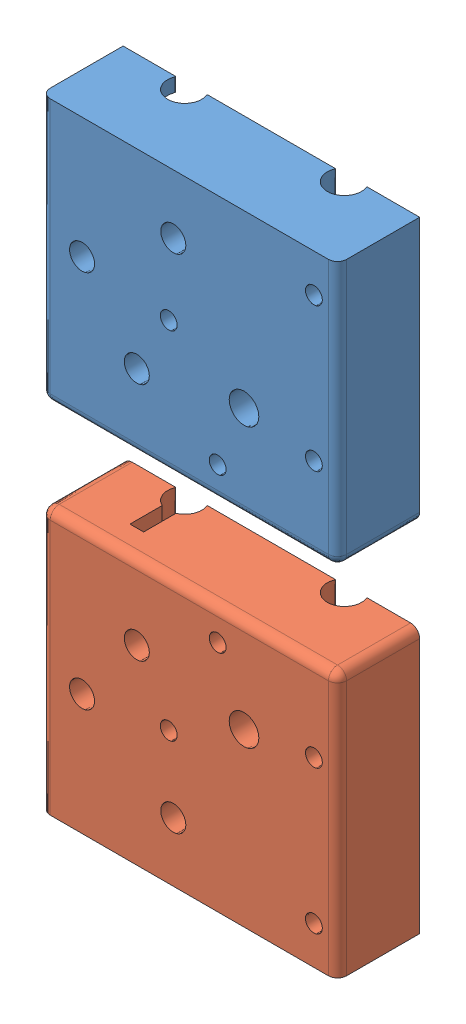
SolidWorks assembly MIRROR_MotorSupportCover, configuration Default. Lengths in mm.
Overall size (65 136 18.47).
2 component instances, 2 part files, 0 mates.
Components (placement in the parent):
- MotorSupportCover-1: MotorSupportCover [Default] at (18.9138 28.7973 47.9878) size (65 58 18.47)
- MirrorMotorSupportCover-2: MirrorMotorSupportCover [Default] at (18.9138 -32.2027 47.9878) x (1 0 0) z (0 0 -1) size (65 58 18.47)
